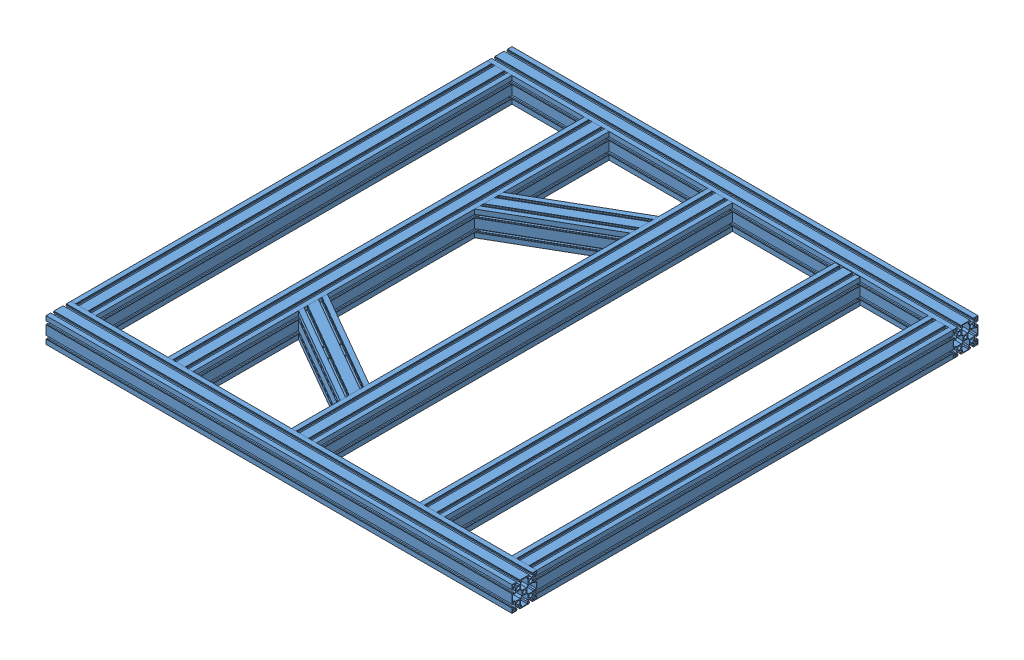
SolidWorks assembly base superior con perfiles, configuration Predeterminado. Lengths in mm.
Overall size (1680 92 1680).
9 component instances, 1 part files, 23 mates.
Components (placement in the parent):
- perfil extruido 90x90-1: perfil extruido 90x90 [1500] at origin size (90 90 1500)
- perfil extruido 90x90-2: perfil extruido 90x90 [1680] at (0 0 795) x (0 0 -1) z (1 0 0) size (90 90 1680)
- perfil extruido 90x90-3: perfil extruido 90x90 [1680] at (0 0 -795) x (0 0 -1) z (1 0 0) size (90 90 1680)
- perfil extruido 90x90-4: perfil extruido 90x90 [1500] at (795 0 0) size (90 90 1500)
- perfil extruido 90x90-5: perfil extruido 90x90 [1500] at (-795 0 0) size (90 90 1500)
- perfil extruido 90x90-6: perfil extruido 90x90 [461] at (-222.4999 0 -420.0224) x (0.5 0 0.866025) z (-0.866025 0 0.5) size (90 90 461.88)
- perfil extruido 90x90-7: perfil extruido 90x90 [461] at (-222.4999 0 420.0224) x (-0.5 0 0.866025) z (0.866025 0 0.5) size (90 90 461.88)
- perfil extruido 90x90-8: perfil extruido 90x90 [1500] at (-444.9998 0 0) size (90 90 1500)
- perfil extruido 90x90-9: perfil extruido 90x90 [1500] at (460 -2 0) size (90 90 1500)
Mates (geometry in assembly coordinates):
- Coincidente1: coincident aligned: plane of perfil extruido 90x90-2 through (0 0 795) normal (1 0 0)
- Coincidente2: coincident aligned: plane of perfil extruido 90x90-3 through (0 0 -795) normal (1 0 0)
- Coincidente3: coincident anti-aligned: plane of perfil extruido 90x90-1 through (0 0 750) normal (0 0 1); plane of perfil extruido 90x90-2 through (840 16.5 750) normal (0 0 -1)
- Coincidente4: coincident aligned: plane of perfil extruido 90x90-1 through (-16.5 45 750) normal (0 1 0); plane of perfil extruido 90x90-2 through (840 45 811.5) normal (0 1 0)
- Coincidente5: coincident anti-aligned: plane of perfil extruido 90x90-1 through (0 0 -750) normal (0 0 -1); plane of perfil extruido 90x90-3 through (840 -16.5 -750) normal (0 0 1)
- Coincidente6: coincident aligned: plane of perfil extruido 90x90-1 through (-16.5 45 750) normal (0 1 0); plane of perfil extruido 90x90-3 through (840 45 -778.5) normal (0 1 0)
- Coincidente7: coincident aligned: plane of perfil extruido 90x90-2 through (840 45 811.5) normal (0 1 0); plane of perfil extruido 90x90-4 through (778.5 45 750) normal (0 1 0)
- Coincidente8: coincident aligned: plane of perfil extruido 90x90-2 through (840 0 795) normal (1 0 0); plane of perfil extruido 90x90-4 through (840 16.5 750) normal (1 0 0)
- Coincidente9: coincident anti-aligned: plane of perfil extruido 90x90-3 through (840 -16.5 -750) normal (0 0 1); plane of perfil extruido 90x90-4 through (795 0 -750) normal (0 0 -1)
- Coincidente10: coincident aligned: plane of perfil extruido 90x90-2 through (840 45 811.5) normal (0 1 0); plane of perfil extruido 90x90-5 through (-811.5 45 750) normal (0 1 0)
- Coincidente11: coincident aligned: plane of perfil extruido 90x90-2 through (-840 0 795) normal (-1 0 0); plane of perfil extruido 90x90-5 through (-840 -16.5 750) normal (-1 0 0)
- Coincidente12: coincident anti-aligned: plane of perfil extruido 90x90-3 through (840 -16.5 -750) normal (0 0 1); plane of perfil extruido 90x90-5 through (-795 0 -750) normal (0 0 -1)
- Coincidente14: coincident aligned: plane of perfil extruido 90x90-1 through (-16.5 45 750) normal (0 1 0); plane of perfil extruido 90x90-6 through (-430.7498 45 -318.8418) normal (0 1 0)
- Coincidente16: coincident aligned: plane of perfil extruido 90x90-1 through (-16.5 45 750) normal (0 1 0); plane of perfil extruido 90x90-7 through (-30.75 45 549.7818) normal (0 1 0)
- Coincidente18: coincident anti-aligned: plane of perfil extruido 90x90-2 through (840 16.5 750) normal (0 0 -1); plane of perfil extruido 90x90-8 through (-444.9998 0 750) normal (0 0 1)
- Coincidente19: coincident aligned: plane of perfil extruido 90x90-2 through (840 45 811.5) normal (0 1 0); plane of perfil extruido 90x90-8 through (-461.4998 45 750) normal (0 1 0)
- Coincidente21: coincident: line of perfil extruido 90x90-2 through (840 43 805.5) axis (-1 0 0); plane of perfil extruido 90x90-9 through (443.5 43 750) normal (0 1 0)
- Coincidente22: coincident anti-aligned: plane of perfil extruido 90x90-2 through (840 16.5 750) normal (0 0 -1); plane of perfil extruido 90x90-9 through (460 -2 750) normal (0 0 1)
- Distancia1: distance = 370 mm anti-aligned: plane of perfil extruido 90x90-1 through (45 16.5 750) normal (1 0 0); plane of perfil extruido 90x90-9 through (415 -18.5 750) normal (-1 0 0)
- Coincidente25: coincident anti-aligned: plane of perfil extruido 90x90-1 through (-45 -16.5 750) normal (-1 0 0); plane of perfil extruido 90x90-7 through (-45 45 470.5405) normal (1 0 0)
- Coincidente26: coincident anti-aligned: plane of perfil extruido 90x90-7 through (-399.9998 45 369.5043) normal (-1 0 0); plane of perfil extruido 90x90-8 through (-399.9998 16.5 750) normal (1 0 0)
- Coincidente27: coincident anti-aligned: plane of perfil extruido 90x90-1 through (-45 -16.5 750) normal (-1 0 0); plane of perfil extruido 90x90-6 through (-45 -45 -470.5405) normal (1 0 0)
- Simétrico1: symmetric aligned: line of perfil extruido 90x90-6 through (-399.9998 -16.5 -265.5812) axis (0 1 0); line of perfil extruido 90x90-7 through (-399.9998 -16.5 265.5812) axis (0 1 0)
